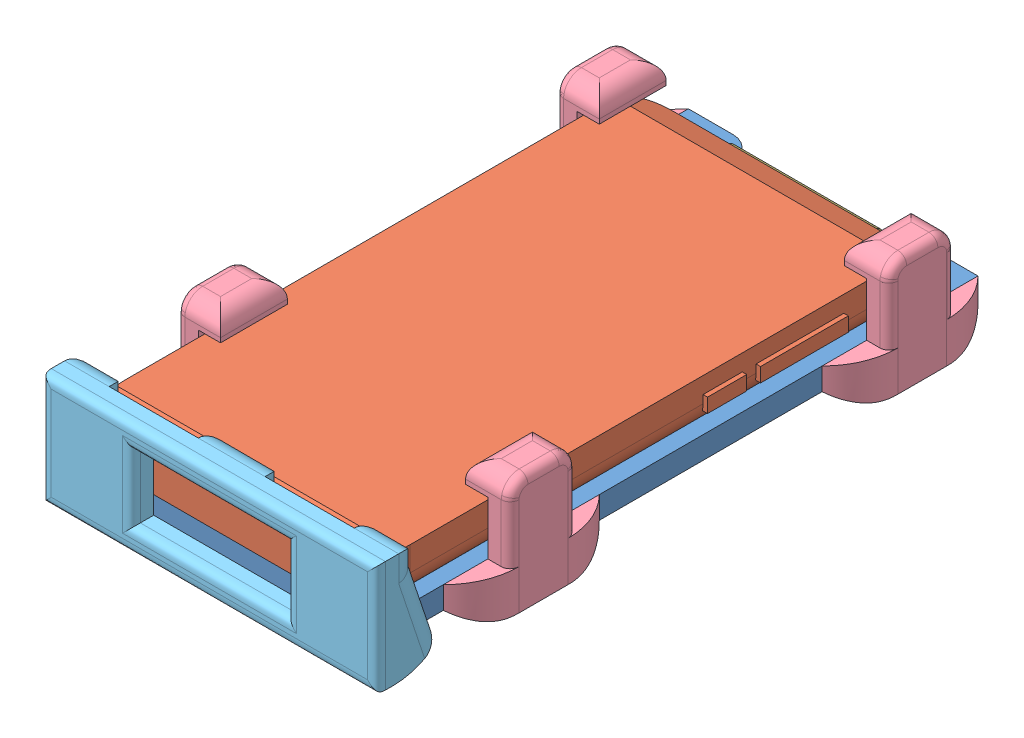
SolidWorks assembly Halterung, configuration Standard. Lengths in mm.
Overall size (75.66 30 140.85).
8 component instances, 5 part files, 21 mates.
Components (placement in the parent):
- Baseplate-1: Baseplate [Standard] at (-33.7713 -0.1953 120) size (65 13 135)
- Handy-1: Handy [Standard] at (30.7287 15.8047 120) x (-1 0 0) z (0 -1 0) size (65.59 125.33 12.67)
- Nubbel-1: Nubbel [Standard] at (-17.7713 4.8047 -10) x (0 0 1) z (-1 0 0) size (5.05 4.9 33.1)
- Klammer Seitlich-1: Klammer Seitlich [Standard] at (36.2287 -4.1953 80) x (0 0 1) z (0 -1 0) size (36.29 15.73 26)
- Klammer Seitlich-2: Klammer Seitlich [Standard] at (-38.7713 -4.1953 95) x (0 0 -1) z (0 -1 0) size (36.29 15.73 26)
- Klammer Seitlich-3: Klammer Seitlich [Standard] at (-38.7713 -4.1953 10) x (0 0 -1) z (0 -1 0) size (36.29 15.73 26)
- Klammer Seitlich-4: Klammer Seitlich [Standard] at (36.2287 -4.1953 -5) x (0 0 1) z (0 -1 0) size (36.29 15.73 26)
- Kammer Unten-1: Kammer Unten [Standard] at (31.2287 -4.1953 125) x (-1 0 0) z (0 0 -1) size (75.66 25.04 15.37)
Mates (geometry in assembly coordinates):
- Deckungsgleich1: coincident anti-aligned: plane of Baseplate-1 through (-33.7713 4.8047 120) normal (0 1 0); plane of Handy-1 through (30.7287 4.8047 120) normal (0 -1 0)
- Deckungsgleich4: coincident aligned: plane of Baseplate-1 through (-33.7713 4.8047 120) normal (0 0 1); plane of Handy-1 through (30.7287 4.8047 120) normal (0 0 1)
- Abstand2: distance = 0.5 mm aligned: plane of Handy-1 through (30.7287 4.8047 120) normal (1 0 0); plane of Baseplate-1 through (31.2287 4.8047 120) normal (1 0 0)
- Deckungsgleich6: coincident anti-aligned: plane of Baseplate-1 through (-33.7713 4.8047 120) normal (0 1 0); plane of Nubbel-1 through (-17.7713 4.8047 -10) normal (0 -1 0)
- Deckungsgleich7: coincident aligned: plane of Baseplate-1 through (15.2287 4.8047 -10) normal (1 0 0); plane of Nubbel-1 through (15.2287 9.8047 -10) normal (1 0 0)
- Tangential1: tangent: plane of Baseplate-1 through (-17.7713 4.8047 -10) normal (0 0 -1); face of Nubbel-1
- Deckungsgleich8: coincident anti-aligned: plane of Baseplate-1 through (-33.7713 0.8047 120) normal (0 -1 0); plane of Klammer Seitlich-1 through (21.2287 0.8047 80) normal (0 1 0)
- Deckungsgleich9: coincident anti-aligned: plane of Baseplate-1 through (31.2287 4.8047 120) normal (1 0 0); plane of Klammer Seitlich-1 through (31.2287 -4.1953 80) normal (-1 0 0)
- Deckungsgleich10: coincident anti-aligned: plane of Baseplate-1 through (31.2287 0.8047 95) normal (0 0 -1); plane of Klammer Seitlich-1 through (31.2287 -4.1953 95) normal (0 0 1)
- Deckungsgleich11: coincident anti-aligned: plane of Baseplate-1 through (-33.7713 0.8047 120) normal (0 -1 0); plane of Klammer Seitlich-4 through (21.2287 0.8047 -5) normal (0 1 0)
- Deckungsgleich12: coincident anti-aligned: plane of Baseplate-1 through (-33.7713 0.8047 120) normal (0 -1 0); plane of Klammer Seitlich-3 through (-23.7713 0.8047 10) normal (0 1 0)
- Deckungsgleich13: coincident anti-aligned: plane of Baseplate-1 through (-33.7713 0.8047 120) normal (0 -1 0); plane of Klammer Seitlich-2 through (-23.7713 0.8047 95) normal (0 1 0)
- Deckungsgleich14: coincident anti-aligned: plane of Baseplate-1 through (31.2287 4.8047 120) normal (1 0 0); plane of Klammer Seitlich-4 through (31.2287 -4.1953 -5) normal (-1 0 0)
- Deckungsgleich15: coincident anti-aligned: plane of Baseplate-1 through (-33.7713 4.8047 120) normal (-1 0 0); plane of Klammer Seitlich-3 through (-33.7713 -4.1953 10) normal (1 0 0)
- Deckungsgleich16: coincident anti-aligned: plane of Baseplate-1 through (-33.7713 4.8047 120) normal (-1 0 0); plane of Klammer Seitlich-2 through (-33.7713 -4.1953 95) normal (1 0 0)
- Deckungsgleich17: coincident anti-aligned: plane of Baseplate-1 through (-33.7713 0.8047 10) normal (0 0 -1); plane of Klammer Seitlich-3 through (-33.7713 -4.1953 10) normal (0 0 1)
- Deckungsgleich18: coincident anti-aligned: plane of Baseplate-1 through (-33.7713 0.8047 95) normal (0 0 -1); plane of Klammer Seitlich-2 through (-33.7713 -4.1953 95) normal (0 0 1)
- Deckungsgleich19: coincident anti-aligned: plane of Baseplate-1 through (31.2287 0.8047 10) normal (0 0 -1); plane of Klammer Seitlich-4 through (31.2287 -4.1953 10) normal (0 0 1)
- Deckungsgleich20: coincident anti-aligned: plane of Baseplate-1 through (-33.7713 4.8047 120) normal (0 0 1); plane of Kammer Unten-1 through (31.2287 -4.1953 120) normal (0 0 -1)
- Deckungsgleich21: coincident anti-aligned: plane of Baseplate-1 through (-33.7713 0.8047 120) normal (0 -1 0); plane of Kammer Unten-1 through (31.2287 0.8047 110) normal (0 1 0)
- Deckungsgleich22: coincident anti-aligned: plane of Baseplate-1 through (-33.7713 4.8047 120) normal (-1 0 0); plane of Kammer Unten-1 through (-33.7713 -4.1953 125) normal (1 0 0)
